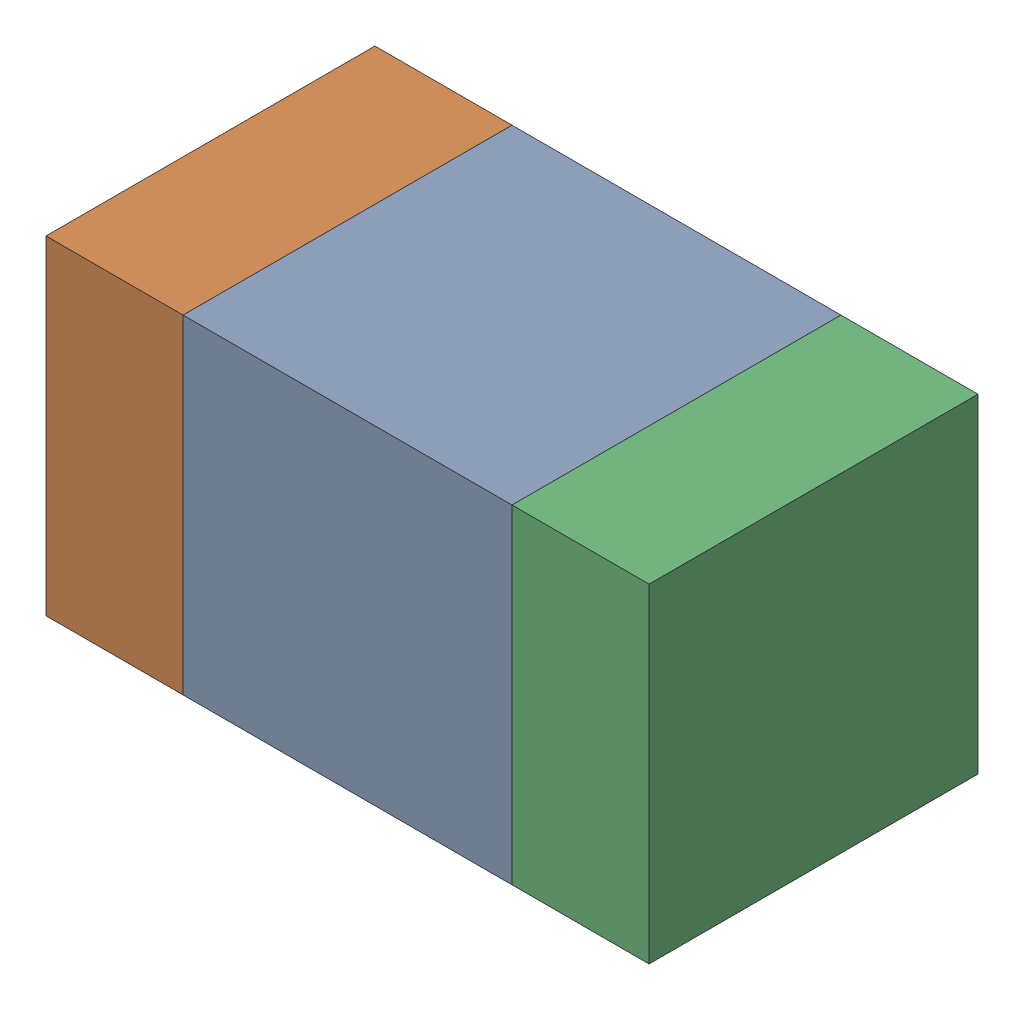
SolidWorks assembly C316_2PCB, configuration Default. Lengths in mm.
Overall size (1.1 0.6 0.6).
6 component instances, 2 part files, 0 mates.
Components (placement in the parent):
- 761606048-1: 761606048 [Default] at (130.6 93.2 -2.2638) size (0.6 0.6 0.6)
  - Extruded_9-1: Extruded_9 [Default] at origin size (0.6 0.6 0.6)
- 854785160-1: 854785160 [Default] at (130.175 93.2 -2.2638) size (0.25 0.6 0.6)
  - Extruded_19-1: Extruded_19 [Default] at origin size (0.25 0.6 0.6)
- 854785160-2: 854785160 [Default] at (131.025 93.2 -2.2638) size (0.25 0.6 0.6)
  - Extruded_19-1: Extruded_19 [Default] at origin size (0.25 0.6 0.6)
